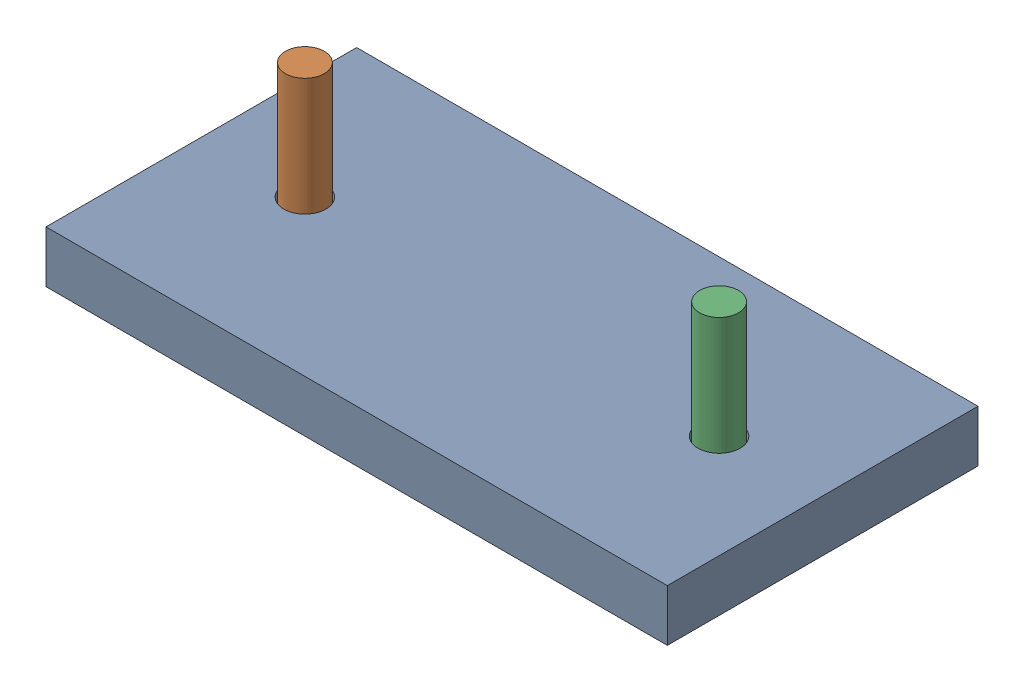
SolidWorks assembly 01-038-00-0, configuration Default. Lengths in mm.
Overall size (304.8 82.55 152.4).
3 component instances, 2 part files, 0 mates.
Components (placement in the parent):
- 01-036-00-0-1: 01-036-00-0 [Default] at origin size (304.8 25.4 152.4)
- 01-037-00-0-1: 01-037-00-0 [Default] at (50.8 19.05 -76.2) size (19.05 63.5 19.05)
- 01-037-00-0-2: 01-037-00-0 [Default] at (254 19.05 -76.2) size (19.05 63.5 19.05)
